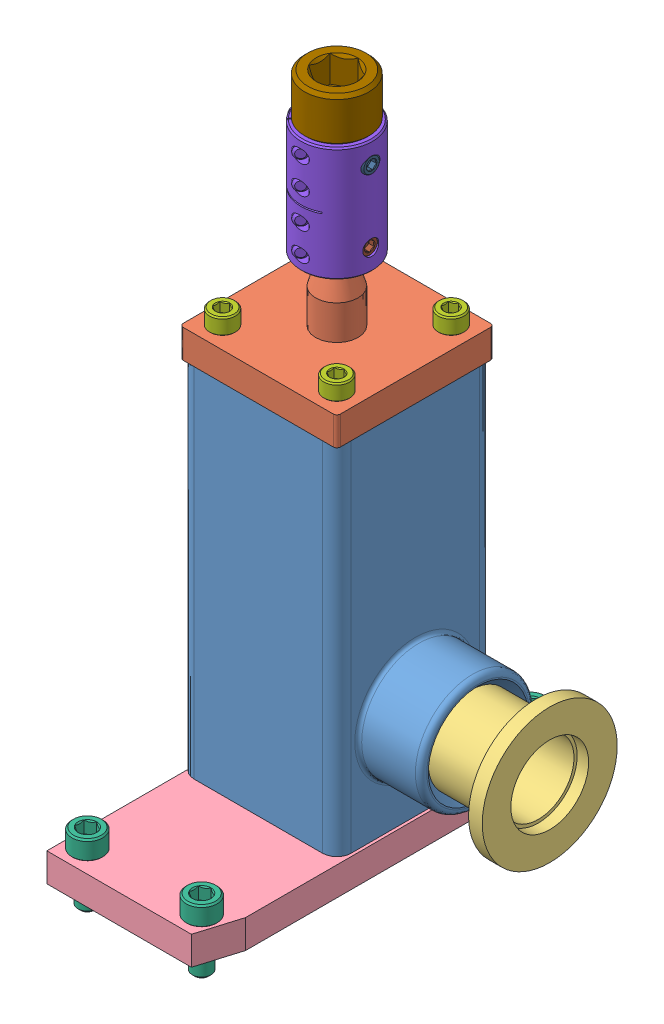
SolidWorks assembly VacValveOffsetAssy, configuration Default. Lengths in mm.
Overall size (73.02 152.86 82.55).
19 component instances, 11 part files, 28 mates.
Components (placement in the parent):
- KeyHigh-BA-75-BrassValve-1: KeyHigh-BA-75-BrassValve [Default] at origin size (48.9 79.38 34.92)
- KeyHigh-KeyHigh-DB-75-BellowAssy-1: KeyHigh-KeyHigh-DB-75-BellowAssy [Default] at (0 52.9955 0) size (34.92 103 34.92)
- KeyHigh-KSF-0816-2-NW16-Flange-Stub-1: KeyHigh-KSF-0816-2-NW16-Flange-Stub [Default] at (34.4034 20.955 0) x (0 -1 0) z (0 0 1) size (29.97 25.4 29.97)
- VacValve-OffsetBase-Alt-1: VacValve-OffsetBase-Alt [Default] at (0 -6.35 0) size (34.92 22.23 82.55)
- O-ringParker-2-118-VacPortOriginal-1: O-ringParker-2-118-VacPortOriginal [Default] at (-6.35 -10.7442 0) x (-0.837169 0 -0.546944) z (-0.546944 0 0.837169) size (27.97 1.95 27.97)
- SHCS-8-32x0.438-92196A193-2: SHCS-8-32x0.438-92196A193 [92196A193] at (-19.05 -17.4625 -36.6395) x (1 0 0) z (0 -1 0) size (6.86 6.86 15.48)
- SHCS-8-32x0.438-92196A193-5: SHCS-8-32x0.438-92196A193 [92196A193] at (-19.05 -17.4625 36.3855) x (1 0 0) z (0 -1 0) size (6.86 6.86 15.48)
- SHCS-8-32x0.438-92196A193-6: SHCS-8-32x0.438-92196A193 [92196A193] at (6.35 -17.4625 -36.6395) x (1 0 0) z (0 -1 0) size (6.86 6.86 15.48)
- SHCS-8-32x0.438-92196A193-7: SHCS-8-32x0.438-92196A193 [92196A193] at (6.35 -17.4625 36.3855) x (1 0 0) z (0 -1 0) size (6.86 6.86 15.48)
- SHCS-6-32x0.438-92196A147-1: SHCS-6-32x0.438-92196A147 [92196A147] at (-12.7 74.6125 -12.7) x (1 0 0) z (0 -1 0) size (5.74 5.74 14.78)
- SHCS-6-32x0.438-92196A147-2: SHCS-6-32x0.438-92196A147 [92196A147] at (-12.7 74.6125 12.7) x (1 0 0) z (0 -1 0) size (5.74 5.74 14.78)
- SHCS-6-32x0.438-92196A147-3: SHCS-6-32x0.438-92196A147 [92196A147] at (12.7 74.6125 -12.7) x (1 0 0) z (0 -1 0) size (5.74 5.74 14.78)
- SHCS-6-32x0.438-92196A147-4: SHCS-6-32x0.438-92196A147 [92196A147] at (12.7 74.6125 12.7) x (1 0 0) z (0 -1 0) size (5.74 5.74 14.78)
- VacValveStemCoupling61005K411-1: VacValveStemCoupling61005K411 [61005K411] at (0 112.7125 0) x (0 1 0) z (-0.725046 0 0.688701) size (25.4 15.88 15.87)
- VacValveStemHexInterface-1: VacValveStemHexInterface [92196A621] at (0 109.5375 0) x (0.99967 0 0.0257) z (0 -1 0) size (14.29 14.29 20.78)
- SetScrew-8-32x3_16-94355A182-1: SetScrew-8-32x3_16-94355A182 [94355A182] at (5.5544 120.65 0.1428) x (0.018173 -0.707107 -0.706873) z (0.99967 0 0.0257) size (4.17 4.17 4.88)
- SetScrew-8-32x3_16-94355A182-2: SetScrew-8-32x3_16-94355A182 [94355A182] at (0.1428 120.65 -5.5544) x (-0.99967 0 -0.0257) z (0.0257 0 -0.99967) size (4.17 4.17 4.88)
- SetScrew-8-32x3_16-94355A182-4: SetScrew-8-32x3_16-94355A182 [94355A182] at (0.1428 104.775 -5.5544) x (-0.99967 0 -0.0257) z (0.0257 0 -0.99967) size (4.17 4.17 4.88)
- 92785A192_HIGH HOLD CONE POINT SET SCREW-1: 92785A192_HIGH HOLD CONE POINT SET SCREW [92785A192] at (2.7321 104.775 0.0702) x (0.0257 0 -0.99967) z (0.99967 0 0.0257) size (4.17 4.17 9.64)
Mates (geometry in assembly coordinates):
- Concentric1: concentric anti-aligned: cylinder of KeyHigh-BA-75-BrassValve-1 through (0 79.375 0) axis (0 1 0) radius 11.5189; cylinder of KeyHigh-KeyHigh-DB-75-BellowAssy-1 through (0 8.128 0) axis (0 -1 0) radius 10.9855
- Concentric2: concentric aligned: cylinder of KeyHigh-BA-75-BrassValve-1 through (12.7 79.375 12.7) axis (0 1 0) radius 1.7272; cylinder of KeyHigh-KeyHigh-DB-75-BellowAssy-1 through (12.7 85.725 12.7) axis (0 1 0) radius 2.2479
- Coincident1: coincident anti-aligned: plane of KeyHigh-BA-75-BrassValve-1 through (0 79.375 0) normal (0 1 0); plane of KeyHigh-KeyHigh-DB-75-BellowAssy-1 through (0 79.375 17.4625) normal (0 -1 0)
- Concentric3: concentric aligned: cylinder of KeyHigh-BA-75-BrassValve-1 through (31.4325 20.955 0) axis (1 0 0) radius 9.525; cylinder of KeyHigh-KSF-0816-2-NW16-Flange-Stub-1 through (47.3075 20.955 0) axis (1 0 0) radius 9.5123
- Coincident2: coincident anti-aligned: plane of KeyHigh-BA-75-BrassValve-1 through (21.9075 28.8925 0) normal (1 0 0); plane of KeyHigh-KSF-0816-2-NW16-Flange-Stub-1 through (21.9075 20.955 -7.9375) normal (-1 0 0)
- Concentric4: concentric aligned: cylinder of KeyHigh-BA-75-BrassValve-1 through (0 9.525 0) axis (0 -1 0) radius 9.525; cylinder of VacValve-OffsetBase-Alt-1 through (0 9.525 0) axis (0 -1 0) radius 9.5123
- Coincident3: coincident anti-aligned: plane of KeyHigh-BA-75-BrassValve-1 through (0 9.525 0) normal (0 -1 0); plane of VacValve-OffsetBase-Alt-1 through (0 9.525 0) normal (0 1 0)
- Parallel1: parallel aligned: plane of KeyHigh-BA-75-BrassValve-1 through (-17.4625 79.375 0) normal (-1 0 0); plane of VacValve-OffsetBase-Alt-1 through (-23.1648 -12.7 0) normal (-1 0 0)
- Coincident5: coincident aligned: plane of KeyHigh-BA-75-BrassValve-1 through (0 0 0) normal (0 0 1); plane of assembly through (0 0 0) normal (0 0 1)
- Coincident6: coincident aligned: plane of KeyHigh-BA-75-BrassValve-1 through (0 0 0) normal (1 0 0); plane of assembly through (0 0 0) normal (1 0 0)
- Coincident7: coincident aligned: plane of KeyHigh-BA-75-BrassValve-1 through (0 0 0) normal (0 1 0); plane of assembly through (0 0 0) normal (0 1 0)
- Coincident8: coincident anti-aligned: plane of VacValve-OffsetBase-Alt-1 through (0 -10.7442 0) normal (0 -1 0); plane of O-ringParker-2-118-VacPortOriginal-1 through (-6.35 -10.7442 0) normal (0 1 0)
- Concentric5: concentric anti-aligned: cylinder of VacValve-OffsetBase-Alt-1 through (-6.35 -10.7442 0) axis (0 -1 0) radius 10.9474; cylinder of O-ringParker-2-118-VacPortOriginal-1 through (-6.35 -12.6942 0) axis (0 1 0) radius 10.9474
- Coincident9: coincident anti-aligned: plane of VacValve-OffsetBase-Alt-1 through (0 -6.35 0) normal (0 1 0); plane of SHCS-8-32x0.438-92196A193-2 through (-19.05 -6.35 -36.6395) normal (0 -1 0)
- Concentric6: concentric aligned: cylinder of VacValve-OffsetBase-Alt-1 through (-19.05 -12.7 -36.6395) axis (0 -1 0) radius 2.2479; cylinder of SHCS-8-32x0.438-92196A193-2 through (-19.05 -6.35 -36.6395) axis (0 -1 0) radius 2.0828
- Coincident10: coincident anti-aligned: plane of KeyHigh-KeyHigh-DB-75-BellowAssy-1 through (0 85.725 4.7117) normal (0 1 0); plane of SHCS-6-32x0.438-92196A147-1 through (-12.7 85.725 -12.7) normal (0 -1 0)
- Concentric7: concentric anti-aligned: cylinder of KeyHigh-KeyHigh-DB-75-BellowAssy-1 through (-12.7 85.725 -12.7) axis (0 1 0) radius 2.2479; cylinder of SHCS-6-32x0.438-92196A147-1 through (-12.7 85.725 -12.7) axis (0 -1 0) radius 1.7526
- Coincident11: coincident anti-aligned: plane of VacValveStemCoupling61005K411-1 through (5.7551 125.4125 -5.4666) normal (0 1 0); plane of VacValveStemHexInterface-1 through (0 125.4125 0) normal (0 -1 0)
- Concentric8: concentric aligned: cylinder of VacValveStemCoupling61005K411-1 through (0 100.0125 0) axis (0 -1 0) radius 3.175; cylinder of VacValveStemHexInterface-1 through (0 125.4125 0) axis (0 -1 0) radius 3.1623
- Angle1: planar angle = 2.356194 rad aligned: plane of VacValveStemHexInterface-1 through (-0.0682 109.5375 2.6534) normal (-0.0257 0 0.99967); plane of VacValveStemCoupling61005K411-1 through (0.1093 100.0125 0.1151) normal (-0.688701 0 -0.725046)
- Concentric14: concentric anti-aligned: cylinder of VacValveStemCoupling61005K411-1 through (0.204 120.65 -7.9349) axis (0.0257 0 -0.99967) radius 1.7272; cylinder of SetScrew-8-32x3_16-94355A182-2 through (0.0816 120.65 -3.174) axis (-0.0257 0 0.99967) radius 2.0828
- Tangent3: tangent anti-aligned: cylinder of VacValveStemCoupling61005K411-1 through (0 100.0125 0) axis (0 -1 0) radius 3.175; plane of SetScrew-8-32x3_16-94355A182-2 through (0.0816 120.65 -3.174) normal (-0.0257 0 0.99967)
- Concentric16: concentric anti-aligned: cylinder of VacValveStemCoupling61005K411-1 through (7.9349 120.65 0.204) axis (0.99967 0 0.0257) radius 1.7272; cylinder of SetScrew-8-32x3_16-94355A182-1 through (3.174 120.65 0.0816) axis (-0.99967 0 -0.0257) radius 2.0828
- Tangent6: tangent anti-aligned: cylinder of VacValveStemCoupling61005K411-1 through (0 100.0125 0) axis (0 -1 0) radius 3.175; plane of SetScrew-8-32x3_16-94355A182-1 through (3.174 120.65 0.0816) normal (-0.99967 0 -0.0257)
- Concentric17: concentric aligned: cylinder of KeyHigh-KeyHigh-DB-75-BellowAssy-1 through (0 8.128 0) axis (0 -1 0) radius 3.1369; cylinder of VacValveStemCoupling61005K411-1 through (0 100.0125 0) axis (0 -1 0) radius 3.175
- Concentric18: concentric aligned: cylinder of KeyHigh-KeyHigh-DB-75-BellowAssy-1 through (3.1359 104.775 0.0806) axis (0.99967 0 0.0257) radius 2.3813; cylinder of VacValveStemCoupling61005K411-1 through (7.9349 104.775 0.204) axis (0.99967 0 0.0257) radius 1.7272
- Concentric19: concentric: cylinder of KeyHigh-KeyHigh-DB-75-BellowAssy-1 through (3.1359 104.775 0.0806) axis (0.99967 0 0.0257) radius 2.3813; cylinder of 92785A192_HIGH HOLD CONE POINT SET SCREW-1 through (13.3984 104.775 0.3445) axis (-0.99967 0 -0.0257) radius 2.0828
- Coincident12: coincident: cone of KeyHigh-KeyHigh-DB-75-BellowAssy-1 through (-0.0381 104.775 -0.001) axis (-0.99967 0 -0.0257); circle of 92785A192_HIGH HOLD CONE POINT SET SCREW-1
